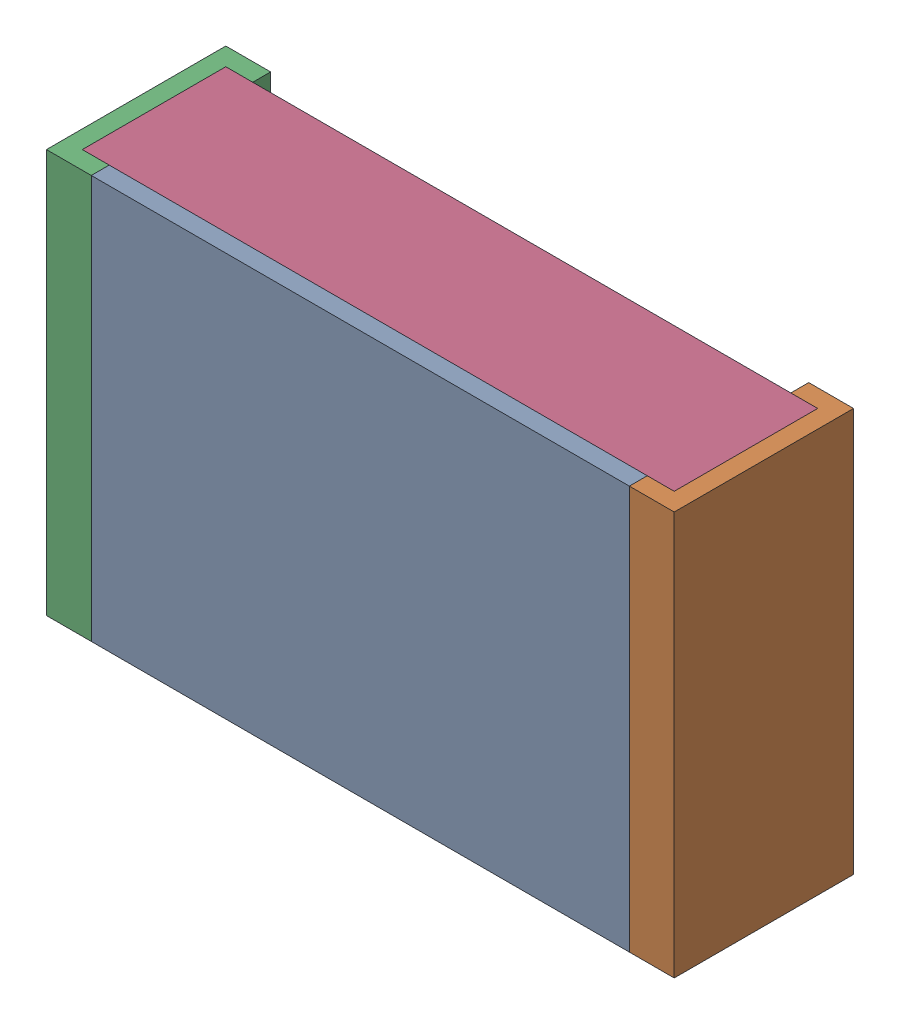
SolidWorks assembly R51, configuration По умолчанию. Lengths in mm.
Overall size (2.1 1.35 0.6).
5 component instances, 3 part files, 0 mates.
Components (placement in the parent):
- RESC2012X06N.step-2-1: RESC2012X06N.step-2 [По умолчанию] at origin size (2.1 1.35 0.6)
  - RESC2012X06N.step-Part-1-1: RESC2012X06N.step-Part-1 [По умолчанию] at (-0.9 -0.675 0.54) size (1.8 1.35 0.06)
  - RESC2012X06N.step-Part-2-1: RESC2012X06N.step-Part-2 [По умолчанию] at (1.05 0.675 0) x (-1 0 0) z (0 0 1) size (0.15 1.35 0.6)
  - RESC2012X06N.step-Part-2-2: RESC2012X06N.step-Part-2 [По умолчанию] at (-1.05 -0.675 0) size (0.15 1.35 0.6)
  - RESC2012X06N.step-Part-3-1: RESC2012X06N.step-Part-3 [По умолчанию] at (-1.05 -0.675 0) size (1.98 1.35 0.48)
